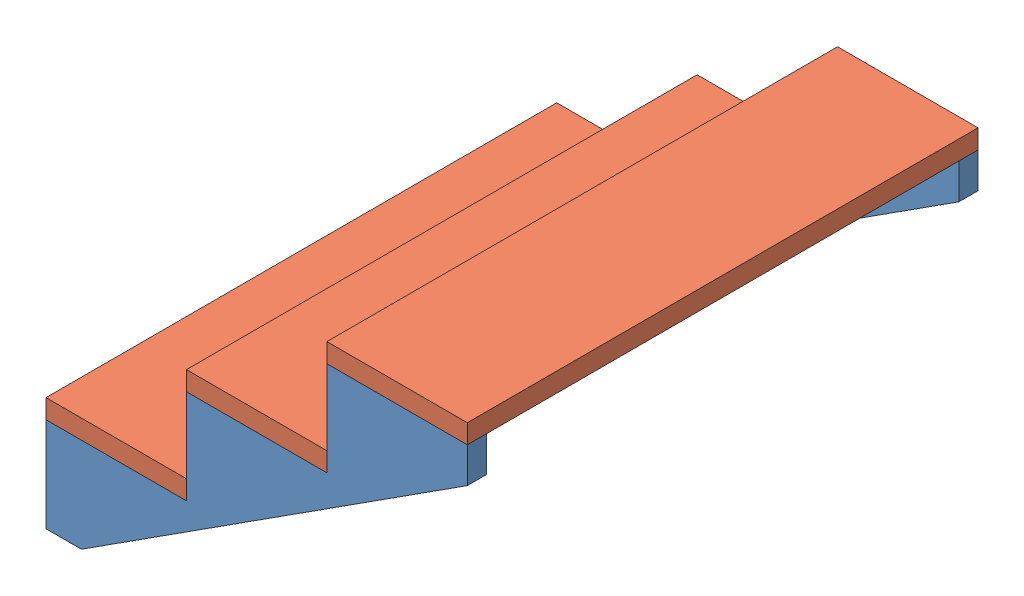
SolidWorks assembly Stair Assembly, configuration Default. Lengths in mm.
Overall size (838.2 601.98 1016).
5 component instances, 2 part files, 12 mates.
Components (placement in the parent):
- Stair-1: Stair [Default] at origin size (838.2 563.88 38.1)
- Stair-2: Stair [Default] at (0 0 977.9) size (838.2 563.88 38.1)
- Stair Slab-1: Stair Slab [Default] at (139.7 187.96 508) x (0 0 1) z (-1 0 0) size (1016 38.1 279.4)
- Stair Slab-2: Stair Slab [Default] at (419.1 375.92 508) x (0 0 1) z (-1 0 0) size (1016 38.1 279.4)
- Stair Slab-3: Stair Slab [Default] at (698.5 563.88 508) x (0 0 1) z (-1 0 0) size (1016 38.1 279.4)
Mates (geometry in assembly coordinates):
- Coincident1: coincident aligned: line of Stair-1 through (279.4 279.4 187.96) axis (0 -1 0); line of Stair Slab-1 through (279.4 279.4 187.96) axis (0 -1 0)
- Coincident2: coincident aligned: plane of Stair-1 through (0 187.96 38.1) normal (-1 0 0); plane of Stair Slab-1 through (0 226.06 0) normal (-1 0 0)
- Coincident3: coincident anti-aligned: plane of Stair-1 through (0 187.96 38.1) normal (0 1 0); plane of Stair Slab-1 through (139.7 187.96 508) normal (0 -1 0)
- Coincident4: coincident anti-aligned: plane of Stair-1 through (279.4 375.92 38.1) normal (0 1 0); plane of Stair Slab-2 through (419.1 375.92 508) normal (0 -1 0)
- Coincident5: coincident aligned: line of Stair-1 through (279.4 558.8 375.92) axis (0 -1 0); line of Stair Slab-2 through (279.4 558.8 375.92) axis (0 -1 0)
- Coincident6: coincident aligned: plane of Stair-1 through (279.4 187.96 38.1) normal (-1 0 0); plane of Stair Slab-2 through (279.4 414.02 0) normal (-1 0 0)
- Coincident7: coincident anti-aligned: plane of Stair-1 through (558.8 563.88 38.1) normal (0 1 0); plane of Stair Slab-3 through (698.5 563.88 508) normal (0 -1 0)
- Coincident8: coincident aligned: plane of Stair-1 through (0 0 0) normal (0 0 -1); plane of Stair Slab-3 through (838.2 601.98 0) normal (0 0 -1)
- Coincident9: coincident aligned: plane of Stair-1 through (558.8 375.92 38.1) normal (-1 0 0); plane of Stair Slab-3 through (558.8 601.98 0) normal (-1 0 0)
- Distance1: distance = 939.8 mm anti-aligned: plane of Stair-2 through (0 0 977.9) normal (0 0 -1); plane of Stair-1 through (0 0 38.1) normal (0 0 1)
- Coincident12: coincident aligned: plane of Stair-1 through (0 187.96 38.1) normal (-1 0 0); plane of Stair-2 through (0 187.96 1016) normal (-1 0 0)
- Coincident15: coincident aligned: plane of Stair-1 through (0 0 38.1) normal (0 -1 0); plane of Stair-2 through (0 0 1016) normal (0 -1 0)
